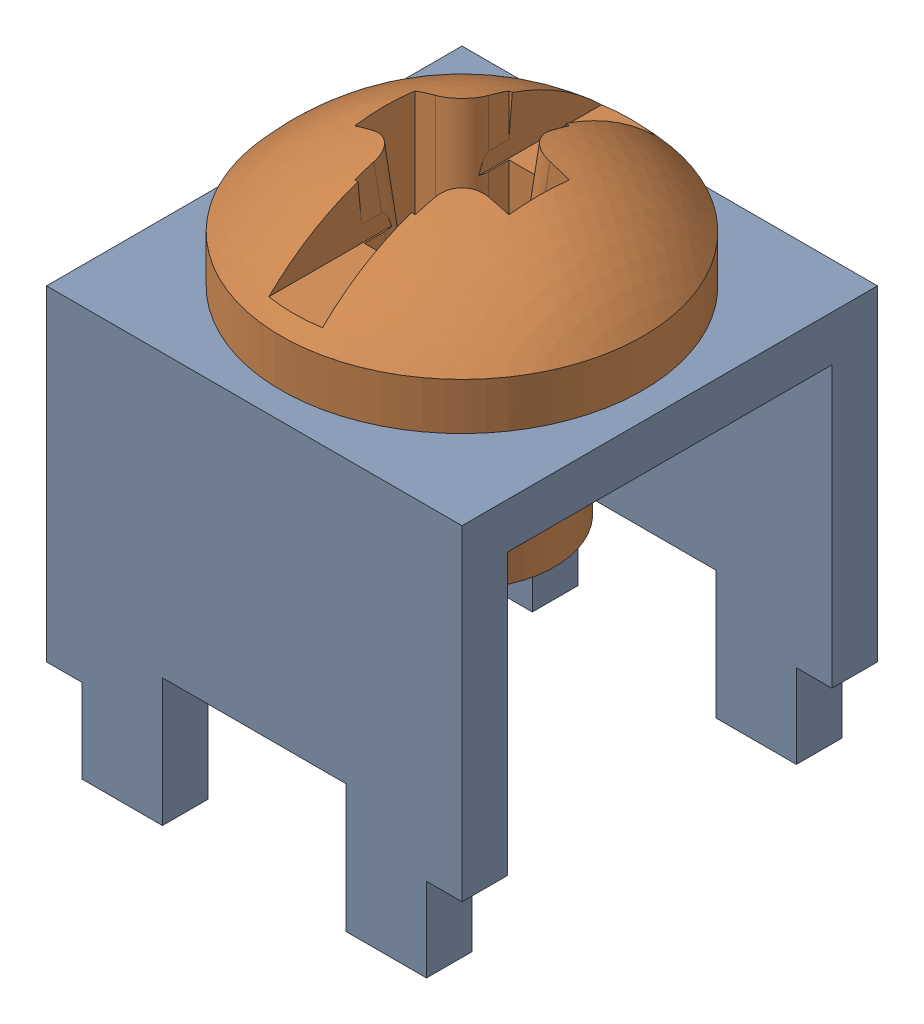
SolidWorks assembly C-SCREW-TERMINAL-7701_ASM, configuration Default. Lengths in mm.
Overall size (7.87 10.19 7.87).
2 component instances, 2 part files, 0 mates.
Components (placement in the parent):
- C-ST-7701-BASE-1: C-ST-7701-BASE [Default] at origin size (7.87 7.76 7.87)
- 6-PH-SCREW-25-1: 6-PH-SCREW-25 [Default] at (0 11.176 0) size (6.86 7.18 6.86)
